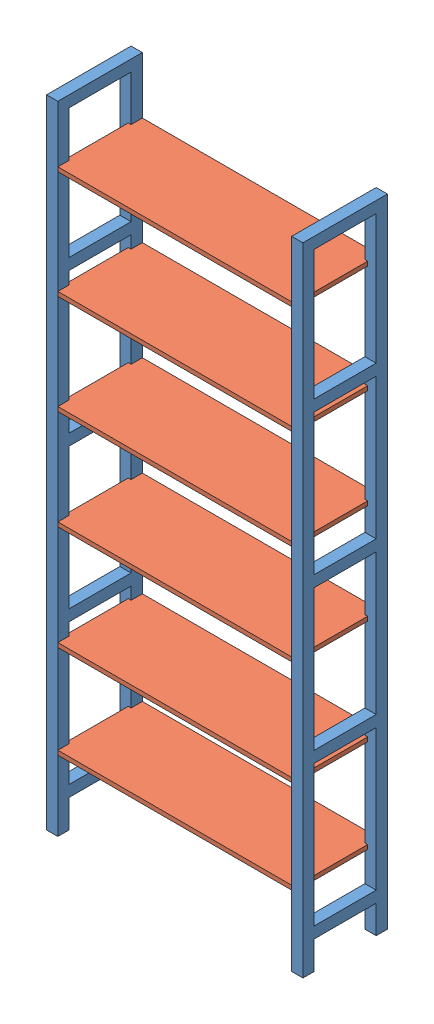
SolidWorks assembly Küchenregal, configuration Standard. Lengths in mm.
Overall size (910 2260 300).
8 component instances, 2 part files, 15 mates.
Components (placement in the parent):
- Seite-30-226-1: Seite-30-226 [Standard] at (-238.8637 -1.8239 2260) size (40 2260 300)
- Seite-30-226-2: Seite-30-226 [Standard] at (631.1363 -1.8239 2260) size (40 2260 300)
- Boden-30-83-1: Boden-30-83 [Standard] at (216.1363 911.7275 2260) size (850 15 300)
- Boden-30-83-2: Boden-30-83 [Standard] at (216.1363 528.716 2260) size (850 15 300)
- Boden-30-83-3: Boden-30-83 [Standard] at (216.1363 174.8864 2260) size (850 15 300)
- Boden-30-83-4: Boden-30-83 [Standard] at (216.1363 -179.7181 2260) size (850 15 300)
- Boden-30-83-5: Boden-30-83 [Standard] at (216.1363 -550.7434 2260) size (850 15 300)
- Boden-30-83-6: Boden-30-83 [Standard] at (216.1363 -881.6449 2260) size (850 15 300)
Mates (geometry in assembly coordinates):
- Deckungsgleich1: coincident anti-aligned: plane of Seite-30-226-1 through (-198.8637 -1.8239 2260) normal (1 0 0); plane of Boden-30-83-1 through (-198.8637 926.7275 2370) normal (-1 0 0)
- Deckungsgleich2: coincident: plane of Seite-30-226-1 through (-198.8637 -1.8239 2260) normal (1 0 0); plane of Boden-30-83-2 through (-198.8637 543.716 2370) normal (-1 0 0)
- Deckungsgleich3: coincident: plane of Seite-30-226-1 through (-198.8637 -1.8239 2260) normal (1 0 0); plane of Boden-30-83-3 through (-198.8637 189.8864 2370) normal (-1 0 0)
- Deckungsgleich4: coincident: plane of Seite-30-226-1 through (-198.8637 -1.8239 2260) normal (1 0 0); plane of Boden-30-83-4 through (-198.8637 -164.7181 2370) normal (-1 0 0)
- Deckungsgleich5: coincident: plane of Seite-30-226-1 through (-198.8637 -1.8239 2260) normal (1 0 0); plane of Boden-30-83-6 through (-198.8637 -866.6449 2370) normal (-1 0 0)
- Deckungsgleich6: coincident aligned: plane of Seite-30-226-1 through (-198.8637 1128.1761 2410) normal (0 0 1); plane of Boden-30-83-6 through (-198.8637 -866.6449 2410) normal (0 0 1)
- Deckungsgleich7: coincident: plane of Seite-30-226-1 through (-198.8637 1128.1761 2410) normal (0 0 1); plane of Boden-30-83-5 through (-198.8637 -535.7434 2410) normal (0 0 1)
- Deckungsgleich8: coincident anti-aligned: plane of Seite-30-226-1 through (-198.8637 -1.8239 2260) normal (1 0 0); plane of Boden-30-83-5 through (-198.8637 -535.7434 2370) normal (-1 0 0)
- Deckungsgleich9: coincident aligned: plane of Seite-30-226-1 through (-198.8637 1128.1761 2410) normal (0 0 1); plane of Boden-30-83-4 through (-198.8637 -164.7181 2410) normal (0 0 1)
- Deckungsgleich10: coincident aligned: plane of Seite-30-226-1 through (-198.8637 1128.1761 2410) normal (0 0 1); plane of Boden-30-83-3 through (-198.8637 189.8864 2410) normal (0 0 1)
- Deckungsgleich11: coincident aligned: plane of Seite-30-226-1 through (-198.8637 1128.1761 2410) normal (0 0 1); plane of Boden-30-83-2 through (-198.8637 543.716 2410) normal (0 0 1)
- Deckungsgleich12: coincident aligned: plane of Seite-30-226-1 through (-198.8637 1128.1761 2410) normal (0 0 1); plane of Boden-30-83-1 through (-198.8637 926.7275 2410) normal (0 0 1)
- Deckungsgleich13: coincident aligned: plane of Seite-30-226-2 through (671.1363 1128.1761 2410) normal (0 0 1); plane of Boden-30-83-1 through (-198.8637 926.7275 2410) normal (0 0 1)
- Deckungsgleich14: coincident anti-aligned: plane of Seite-30-226-2 through (631.1363 -1.8239 2260) normal (-1 0 0); plane of Boden-30-83-1 through (631.1363 926.7275 2410) normal (1 0 0)
- Deckungsgleich15: coincident aligned: plane of Seite-30-226-1 through (-198.8637 1128.1761 2410) normal (0 1 0); plane of Seite-30-226-2 through (671.1363 1128.1761 2410) normal (0 1 0)
